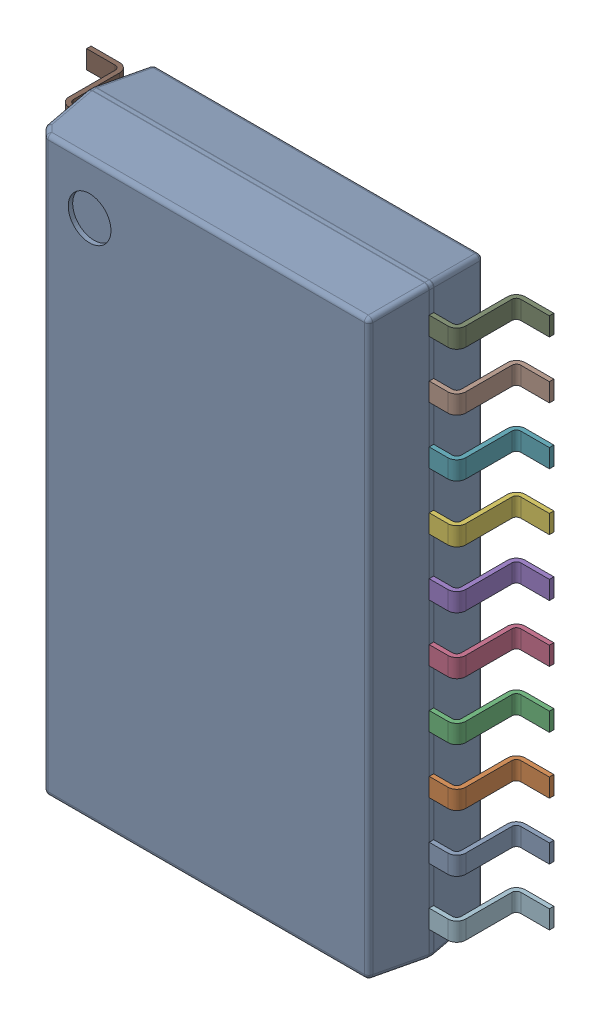
SolidWorks assembly 809572592, configuration Default. Lengths in mm.
Overall size (10.3 13.01 2.66).
23 component instances, 3 part files, 0 mates.
Components (placement in the parent):
- Open_CASCADE_STEP_translator_6.8_1.1-1: Open_CASCADE_STEP_translator_6.8_1.1 [Default] at (-3.8 -6.5 0.001) size (0.95 0.95 0)
- Body_2-1: Body_2 [Default] at (-3.8 -6.5 0) size (7.61 13.01 2.56)
  - Open_CASCADE_STEP_translator_6.8_1.2.1-1: Open_CASCADE_STEP_translator_6.8_1.2.1 [Default] at origin size (7.61 13.01 2.56)
- Leader-1: Leader [Default] at (-3.8 -5.715 0) x (-1 0 0) z (0 0 1) size (1.35 0.41 1.43)
- Leader-2: Leader [Default] at (-3.8 -4.445 0) x (-1 0 0) z (0 0 1) size (1.35 0.41 1.43)
- Leader-3: Leader [Default] at (-3.8 -3.175 0) x (-1 0 0) z (0 0 1) size (1.35 0.41 1.43)
- Leader-4: Leader [Default] at (-3.8 -1.905 0) x (-1 0 0) z (0 0 1) size (1.35 0.41 1.43)
- Leader-5: Leader [Default] at (-3.8 -0.635 0) x (-1 0 0) z (0 0 1) size (1.35 0.41 1.43)
- Leader-6: Leader [Default] at (-3.8 0.635 0) x (-1 0 0) z (0 0 1) size (1.35 0.41 1.43)
- Leader-7: Leader [Default] at (-3.8 1.905 0) x (-1 0 0) z (0 0 1) size (1.35 0.41 1.43)
- Leader-8: Leader [Default] at (-3.8 3.175 0) x (-1 0 0) z (0 0 1) size (1.35 0.41 1.43)
- Leader-9: Leader [Default] at (-3.8 4.445 0) x (-1 0 0) z (0 0 1) size (1.35 0.41 1.43)
- Leader-10: Leader [Default] at (-3.8 5.715 0) x (-1 0 0) z (0 0 1) size (1.35 0.41 1.43)
- Leader-11: Leader [Default] at (3.8 -5.715 0) size (1.35 0.41 1.43)
- Leader-12: Leader [Default] at (3.8 -4.445 0) size (1.35 0.41 1.43)
- Leader-13: Leader [Default] at (3.8 -3.175 0) size (1.35 0.41 1.43)
- Leader-14: Leader [Default] at (3.8 -1.905 0) size (1.35 0.41 1.43)
- Leader-15: Leader [Default] at (3.8 -0.635 0) size (1.35 0.41 1.43)
- Leader-16: Leader [Default] at (3.8 0.635 0) size (1.35 0.41 1.43)
- Leader-17: Leader [Default] at (3.8 1.905 0) size (1.35 0.41 1.43)
- Leader-18: Leader [Default] at (3.8 3.175 0) size (1.35 0.41 1.43)
- Leader-19: Leader [Default] at (3.8 4.445 0) size (1.35 0.41 1.43)
- Leader-20: Leader [Default] at (3.8 5.715 0) size (1.35 0.41 1.43)
